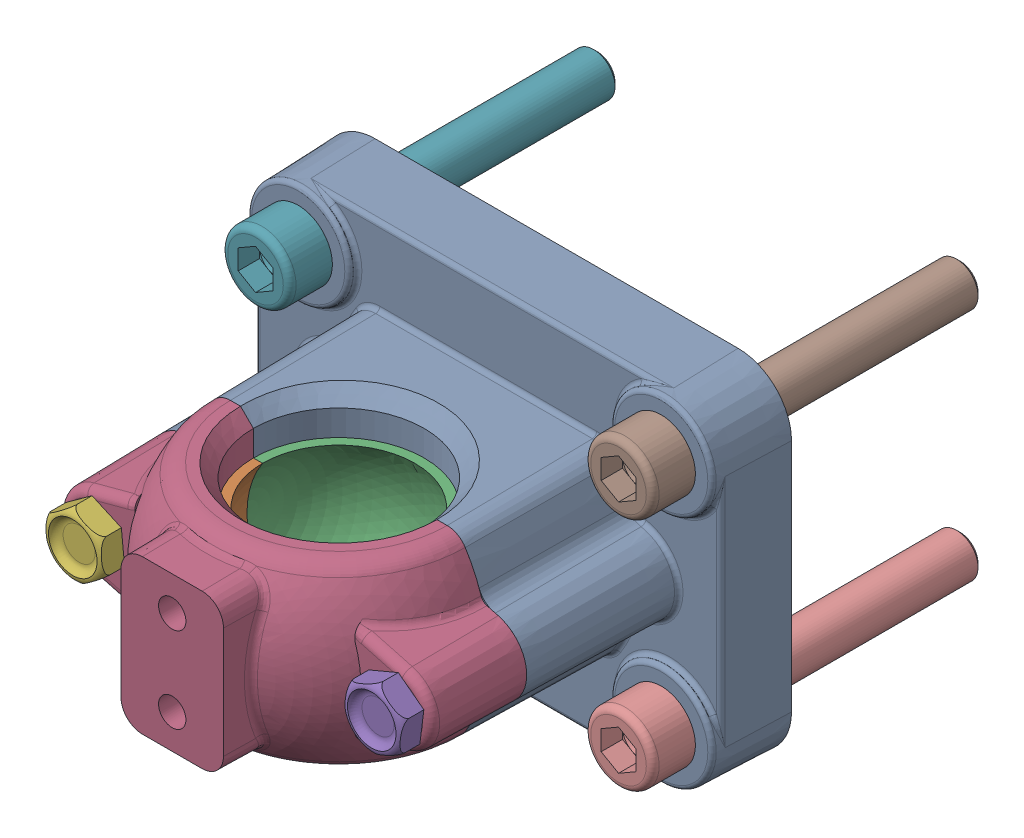
SolidWorks assembly AP_Palier monte, configuration Défaut. Lengths in mm.
Overall size (110.24 80.24 142).
10 component instances, 5 part files, 22 mates.
Components (placement in the parent):
- Palier support VHM32 DTP-1: Palier support VHM32 DTP [Défaut] at origin size (110.24 80.24 51)
- demicoussinet-1: demicoussinet [Défaut] at (0 0 51) x (0 1 0) z (1 0 0) size (25.2 24 52)
- demicoussinet-2: demicoussinet [Défaut] at (0 0 51) x (0 1 0) z (-1 0 0) size (25.2 24 52)
- Couvercle palier V2 H32-1: Couvercle palier V2 H32 [Défaut] at (0 0 51) size (88 42 39)
- vis H-M8-40-1: vis H-M8-40 [M12-1.75 x 45] at (35 0 73) x (0.992169 -0.124905 0) z (0 0 1) size (13.93 15.94 45.5)
- vis H-M8-40-2: vis H-M8-40 [M12-1.75 x 45] at (-35 0 73) x (-0.586563 0.809903 0) z (0 0 1) size (13.93 15.94 45.5)
- Vis CHC M10x70-1: Vis CHC M10x70 [ISO 4762 M10 x 60 --- 60N] at (-42.5 27.5 28) x (0 0 -1) z (1 0 0) size (80 16 16)
- Vis CHC M10x70-2: Vis CHC M10x70 [ISO 4762 M10 x 60 --- 60N] at (42.5 27.5 28) x (0 0 -1) z (1 0 0) size (80 16 16)
- Vis CHC M10x70-3: Vis CHC M10x70 [ISO 4762 M10 x 60 --- 60N] at (-42.5 -27.5 28) x (0 0 -1) z (1 0 0) size (80 16 16)
- Vis CHC M10x70-4: Vis CHC M10x70 [ISO 4762 M10 x 60 --- 60N] at (42.5 -27.5 28) x (0 0 -1) z (1 0 0) size (80 16 16)
Mates (geometry in assembly coordinates):
- Coïncidente1: coincident anti-aligned: plane of Palier support VHM32 DTP-1 through (26 -12 51) normal (0 1 0); plane of demicoussinet-2 through (-17.8396 -12 51) normal (0 -1 0)
- Concentrique1: concentric anti-aligned: cylinder of Palier support VHM32 DTP-1 through (0 26 51) axis (0 1 0) radius 26; cylinder of demicoussinet-2 through (0 -22 51) axis (0 -1 0) radius 26
- Parallèle1: parallel aligned: plane of Palier support VHM32 DTP-1 through (-37.5571 13.7645 51) normal (0 0 1); plane of demicoussinet-2 through (0 0 51) normal (0 0 1)
- Coïncidente2: coincident anti-aligned: plane of assembly through (26 -12 51) normal (0 1 0)
- Concentrique2: concentric anti-aligned: cylinder of Palier support VHM32 DTP-1 through (0 26 51) axis (0 1 0) radius 26; cylinder of demicoussinet-1 through (0 -22 51) axis (0 -1 0) radius 26
- Coïncidente3: coincident anti-aligned: plane of demicoussinet-1 through (0 0 51) normal (0 0 -1); plane of demicoussinet-2 through (0 0 51) normal (0 0 1)
- Sur place1: in place: plane of Palier support VHM32 DTP-1; plane of Couvercle palier V2 H32-1; moOrthogonalPlaneRef_w of Palier support VHM32 DTP-1; plane of Couvercle palier V2 H32-1; moOrthogonalPlaneRef_w of Palier support VHM32 DTP-1; plane of Couvercle palier V2 H32-1
- Coïncidente4: coincident aligned: plane of Palier support VHM32 DTP-1; plane of Couvercle palier V2 H32-1
- Coïncidente5: coincident aligned: moOrthogonalPlaneRef_w of Palier support VHM32 DTP-1; plane of Couvercle palier V2 H32-1
- Coïncidente6: coincident anti-aligned: moOrthogonalPlaneRef_w of Palier support VHM32 DTP-1; plane of Couvercle palier V2 H32-1
- Concentrique3: concentric aligned: cylinder of Couvercle palier V2 H32-1 through (35 0 51) axis (0 0 1) radius 4.5; cylinder of vis H-M8-40-1 through (35 0 33) axis (0 0 1) radius 4
- Concentrique4: concentric aligned: cylinder of Couvercle palier V2 H32-1 through (-35 0 51) axis (0 0 1) radius 4.5; cylinder of vis H-M8-40-2 through (-35 0 33) axis (0 0 1) radius 4
- Coïncidente4: coincident anti-aligned: plane of Couvercle palier V2 H32-1 through (35 0 73) normal (0 0 1); plane of vis H-M8-40-1 through (22.1018 1.6238 73) normal (0 0 -1)
- Coïncidente5: coincident anti-aligned: plane of Couvercle palier V2 H32-1 through (-35 0 73) normal (0 0 1); plane of vis H-M8-40-2 through (-27.3747 -10.5287 73) normal (0 0 -1)
- Coaxiale5: concentric aligned: cylinder of Palier support VHM32 DTP-1 through (-42.5 27.5 0) axis (0 0 1) radius 5.5; cylinder of Vis CHC M10x70-1 through (-42.5 27.5 59.75) axis (0 0 1) radius 5
- Coïncidente10: coincident aligned: plane of Palier support VHM32 DTP-1 through (-42.5 27.5 18) normal (0 0 1); circle of Vis CHC M10x70-1
- Coaxiale6: concentric aligned: cylinder of Palier support VHM32 DTP-1 through (42.5 27.5 0) axis (0 0 1) radius 5.5; cylinder of Vis CHC M10x70-2 through (42.5 27.5 59.75) axis (0 0 1) radius 5
- Coïncidente11: coincident aligned: plane of Palier support VHM32 DTP-1 through (42.5 27.5 18) normal (0 0 1); circle of Vis CHC M10x70-2
- Coaxiale7: concentric aligned: cylinder of Palier support VHM32 DTP-1 through (42.5 -27.5 0) axis (0 0 1) radius 5.5; cylinder of Vis CHC M10x70-4 through (42.5 -27.5 59.75) axis (0 0 1) radius 5
- Coïncidente12: coincident aligned: plane of Palier support VHM32 DTP-1 through (42.5 -27.5 18) normal (0 0 1); circle of Vis CHC M10x70-4
- Coaxiale8: concentric aligned: cylinder of Palier support VHM32 DTP-1 through (-42.5 -27.5 0) axis (0 0 1) radius 5.5; cylinder of Vis CHC M10x70-3 through (-42.5 -27.5 59.75) axis (0 0 1) radius 5
- Coïncidente13: coincident aligned: plane of Palier support VHM32 DTP-1 through (-42.5 -27.5 18) normal (0 0 1); circle of Vis CHC M10x70-3
